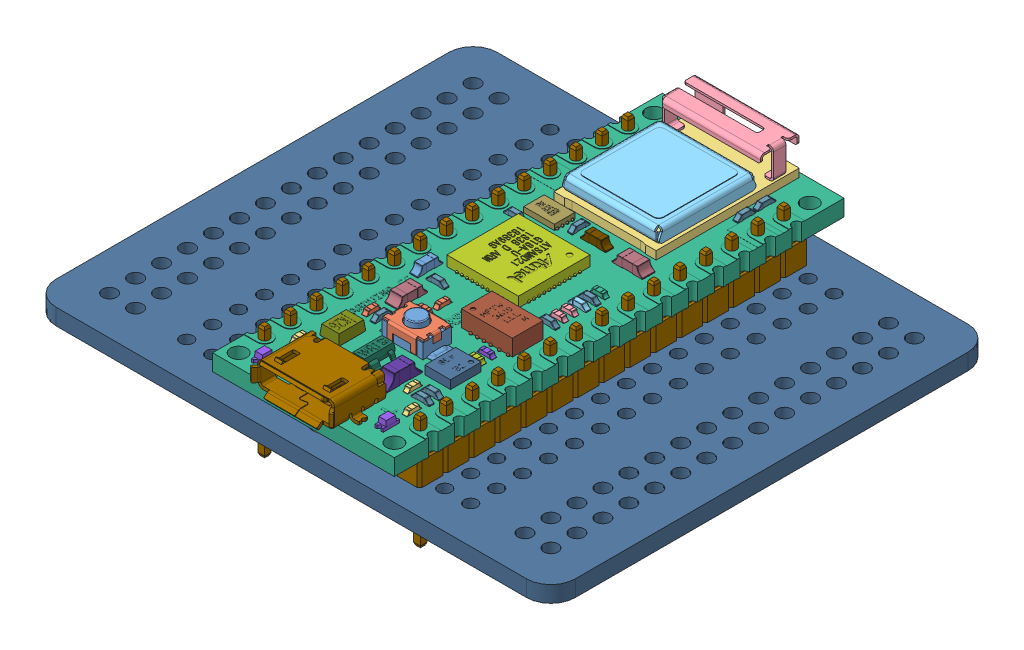
SolidWorks assembly proto assembly, configuration Default. Lengths in mm.
Overall size (50.8 13.8 45.32).
78 component instances, 28 part files, 3 mates.
Components (placement in the parent):
- arduino header subassembly-1: arduino header subassembly [Default] at (-47.2969 18.8882 11.193) size (17.78 13.8 45.32)
  - Arduino Nano 33 IoT.stp-1: Arduino Nano 33 IoT.stp [Default] at origin size (17.78 5.55 45.32)
    - Reser Button.stp-1: Reser Button.stp [Default] at (0 0.8 10.91) size (5.21 2.15 3)
      - User Library-arduino_nano_reset core.stp-1: User Library-arduino_nano_reset core.stp [Default] at origin size (5.21 2.15 2.8)
      - User Library-arduino_nano_reset shell.stp-1: User Library-arduino_nano_reset shell.stp [Default] at (0 1.65 0) x (0 0 1) z (-1 0 0) size (3 1.65 4)
    - NINA-W102 Module.stp-1: NINA-W102 Module.stp [Default] at (0 0.85 -14.5) x (0 0 -1) z (1 0 0) size (14 3.85 10)
      - NINA-W102 Body.stp-1: NINA-W102 Body.stp [Default] at origin size (14 0.85 10)
      - NINA-W102 Antenna.stp-1: NINA-W102 Antenna.stp [Default] at (7 0.8 0) size (3.8 3 10)
      - NINA-W102 Cover.stp-1: NINA-W102 Cover.stp [Default] at (-1.7 2 0) x (0 0 1) z (-1 0 0) size (9.5 1.45 9.6)
    - Nano_33IoT Body.stp-1: Nano_33IoT Body.stp [Default] at origin size (17.78 1.75 44)
    - atmegaSAMD21.stp-1: atmegaSAMD21.stp [Default] at (-1.21 0.82 -0.24) x (0 0 -1) z (1 0 0) size (7.23 1.02 7.23)
    - HSMG-C190 LED.stp-1: HSMG-C190 LED.stp [Default] at (5.79 0.8 19.6) x (0 0 1) z (-1 0 0) size (1.6 0.8 0.8)
    - HSMG-C190 LED.stp-2: HSMG-C190 LED.stp [Default] at (-5.81 0.8 20.1) x (0 0 1) z (-1 0 0) size (1.6 0.8 0.8)
    - ZX62-AB-5PA Micro USB.stp-1: ZX62-AB-5PA Micro USB.stp [Default] at (0 2.22 19.2) size (8.81 3.08 5.64)
    - LSM6DS3 Accelerometer.stp-1: LSM6DS3 Accelerometer.stp [Default] at (4.6275 0.82 12) x (-1 0 0) z (0 0 -1) size (2.5 0.85 3)
    - MPM3610 Step-Down Module.stp-1: MPM3610 Step-Down Module.stp [Default] at (3.69 1.65 6.25) x (0 0 1) z (-1 0 0) size (3.3 1.65 5.15)
    - ATECC608A No Lead Crypto Auth.stp-1: ATECC608A No Lead Crypto Auth.stp [Default] at (-4.035 0.8 -6.08) x (0 0 -1) z (1 0 0) size (2 0.55 3.3)
    - CL21A226MQCLQNC Capacitor.stp-1: CL21A226MQCLQNC Capacitor.stp [Default] at (4.44 1.225 -5.85) x (-1 0 0) z (0 0 -1) size (3 0.85 1.25)
    - TDK C1005 Capacitor.stp-1: TDK C1005 Capacitor.stp [Default] at (5.5825 1.05 -15.55) x (0 0 -1) z (1 0 0) size (1.8 0.5 0.5)
    - TDK C1005 Capacitor.stp-2: TDK C1005 Capacitor.stp [Default] at (5.5825 1.05 -17.5125) x (0 0 -1) z (1 0 0) size (1.8 0.5 0.5)
    - CL21A226MQCLQNC Capacitor.stp-2: CL21A226MQCLQNC Capacitor.stp [Default] at (-4.11 1.225 7.8375) x (0 0 1) z (-1 0 0) size (3 0.85 1.25)
    - TDK C1005 Capacitor.stp-3: TDK C1005 Capacitor.stp [Default] at (5.385 1.05 15.7375) size (1.8 0.5 0.5)
    - TDK C1005 Capacitor.stp-4: TDK C1005 Capacitor.stp [Default] at (5.385 1.05 14.7625) size (1.8 0.5 0.5)
    - PRTR5V0U2X Protection Diode.stp-1: PRTR5V0U2X Protection Diode.stp [Default] at (-0.41 1.45 14.77) x (0 0 -1) z (1 0 0) size (3 1.1 2.5)
    - PMEG6020AELR Diode.stp-1: PMEG6020AELR Diode.stp [Default] at (-4.06 0.85 14.1) x (0 0 1) z (-1 0 0) size (3.3 1.11 1.9)
    - C0805C472KDRACTU Capacitor.stp-1: C0805C472KDRACTU Capacitor.stp [Default] at (2.415 1.425 15.1325) x (0 0 1) z (-1 0 0) size (3.5 1.25 1.25)
    - TDK C1005 Capacitor.stp-5: TDK C1005 Capacitor.stp [Default] at (-1.52 1.05 -6.46) x (0 0 -1) z (1 0 0) size (1.8 0.5 0.5)
    - BLM18PG471SN1D Ferrite Bead.stp-1: BLM18PG471SN1D Ferrite Bead.stp [Default] at (0.61 1.2 -6.1) x (-1 0 0) z (0 0 -1) size (2.5 0.8 0.8)
    - TDK C1005 Capacitor.stp-6: TDK C1005 Capacitor.stp [Default] at (-5.66 1.05 -4.35) x (-1 0 0) z (0 0 -1) size (1.8 0.5 0.5)
    - TDK C1005 Capacitor.stp-7: TDK C1005 Capacitor.stp [Default] at (-3.64 1.05 10.73) x (0 0 1) z (-1 0 0) size (1.8 0.5 0.5)
    - TDK C1005 Capacitor.stp-8: TDK C1005 Capacitor.stp [Default] at (-3.79 1.05 5.1) size (1.8 0.5 0.5)
    - GRM188R61E475KE11D Capacitor.stp-1: GRM188R61E475KE11D Capacitor.stp [Default] at (-5.59 1.2 4.4) x (0 0 1) z (-1 0 0) size (2.5 0.8 0.8)
    - RC0402FR-07100KL Resistor.stp-1: RC0402FR-07100KL Resistor.stp [Default] at (-2.01 1 8.1625) x (-1 0 0) z (0 0 -1) size (1.48 0.48 0.64)
    - RC0402FR-07100KL Resistor.stp-2: RC0402FR-07100KL Resistor.stp [Default] at (-1.6975 1 6.7125) x (0 0 1) z (-1 0 0) size (1.48 0.48 0.64)
    - RC0402FR-07330RL Resistor.stp-1: RC0402FR-07330RL Resistor.stp [Default] at (-5.81 1 16.6) x (0 0 1) z (-1 0 0) size (1.48 0.48 0.64)
    - RC0402FR-07330RL Resistor.stp-2: RC0402FR-07330RL Resistor.stp [Default] at (5.8025 1 17.2) x (0 0 1) z (-1 0 0) size (1.48 0.48 0.64)
    - RC0402FR-07330RL Resistor.stp-3: RC0402FR-07330RL Resistor.stp [Default] at (3.915 1 15.2325) x (0 0 1) z (-1 0 0) size (1.48 0.48 0.64)
    - TDK C1005 Capacitor.stp-9: TDK C1005 Capacitor.stp [Default] at (5.09 1.05 3.1) x (-1 0 0) z (0 0 -1) size (1.8 0.5 0.5)
    - RC0402FR-074K7L Resistor.stp-1: RC0402FR-074K7L Resistor.stp [Default] at (5.09 1 2.1) size (1.48 0.48 0.64)
    - RC0402FR-074K7L Resistor.stp-2: RC0402FR-074K7L Resistor.stp [Default] at (5.09 1 1.1) x (-1 0 0) z (0 0 -1) size (1.48 0.48 0.64)
    - GRM155R61E105KA12D Capacitor.stp-1: GRM155R61E105KA12D Capacitor.stp [Default] at (5.09 1.05 0.1) size (1.8 0.5 0.5)
    - TDK C1005 Capacitor.stp-10: TDK C1005 Capacitor.stp [Default] at (5.09 1.05 -0.9) x (-1 0 0) z (0 0 -1) size (1.8 0.5 0.5)
    - RC0402FR-071KL Resistor.stp-1: RC0402FR-071KL Resistor.stp [Default] at (5.09 1 -1.9) x (-1 0 0) z (0 0 -1) size (1.48 0.48 0.64)
    - RC0402FR-07100KL Resistor.stp-3: RC0402FR-07100KL Resistor.stp [Default] at (-5.74 1 -13.5) x (0 0 -1) z (1 0 0) size (1.48 0.48 0.64)
    - RC0402FR-07100KL Resistor.stp-4: RC0402FR-07100KL Resistor.stp [Default] at (-4.64 1 10.73) x (0 0 1) z (-1 0 0) size (1.48 0.48 0.64)
    - AC0402JR-0724KL Resistor.stp-1: AC0402JR-0724KL Resistor.stp [Default] at (4.665 0.985 9.725) size (1.48 0.39 0.56)
    - AC0402JR-0775KL Resistor.stp-1: AC0402JR-0775KL Resistor.stp [Default] at (4.665 0.985 8.725) size (1.48 0.39 0.56)
  - 1x_Male_Pin_2.54_mm-1: 1x_Male_Pin_2.54_mm [Default] at (-7.945 2.15 -17.695) x (0 0 1) z (1 0 0) size (2.54 11.1 2.4)
  - 1x_Male_Pin_2.54_mm-2: 1x_Male_Pin_2.54_mm [Default] at (7.295 2.15 -17.695) x (0 0 1) z (1 0 0) size (2.54 11.1 2.4)
  - 1x_Male_Pin_2.54_mm-3: 1x_Male_Pin_2.54_mm [Default] at (-7.945 2.15 -15.155) x (0 0 1) z (1 0 0) size (2.54 11.1 2.4)
  - 1x_Male_Pin_2.54_mm-4: 1x_Male_Pin_2.54_mm [Default] at (7.295 2.15 -15.155) x (0 0 1) z (1 0 0) size (2.54 11.1 2.4)
  - 1x_Male_Pin_2.54_mm-5: 1x_Male_Pin_2.54_mm [Default] at (-7.945 2.15 -12.615) x (0 0 1) z (1 0 0) size (2.54 11.1 2.4)
  - 1x_Male_Pin_2.54_mm-6: 1x_Male_Pin_2.54_mm [Default] at (7.295 2.15 -12.615) x (0 0 1) z (1 0 0) size (2.54 11.1 2.4)
  - 1x_Male_Pin_2.54_mm-7: 1x_Male_Pin_2.54_mm [Default] at (-7.945 2.15 -10.075) x (0 0 1) z (1 0 0) size (2.54 11.1 2.4)
  - 1x_Male_Pin_2.54_mm-8: 1x_Male_Pin_2.54_mm [Default] at (7.295 2.15 -10.075) x (0 0 1) z (1 0 0) size (2.54 11.1 2.4)
  - 1x_Male_Pin_2.54_mm-9: 1x_Male_Pin_2.54_mm [Default] at (-7.945 2.15 -7.535) x (0 0 1) z (1 0 0) size (2.54 11.1 2.4)
  - 1x_Male_Pin_2.54_mm-10: 1x_Male_Pin_2.54_mm [Default] at (7.295 2.15 -7.535) x (0 0 1) z (1 0 0) size (2.54 11.1 2.4)
  - 1x_Male_Pin_2.54_mm-11: 1x_Male_Pin_2.54_mm [Default] at (-7.945 2.15 -4.995) x (0 0 1) z (1 0 0) size (2.54 11.1 2.4)
  - 1x_Male_Pin_2.54_mm-12: 1x_Male_Pin_2.54_mm [Default] at (7.295 2.15 -4.995) x (0 0 1) z (1 0 0) size (2.54 11.1 2.4)
  - 1x_Male_Pin_2.54_mm-13: 1x_Male_Pin_2.54_mm [Default] at (-7.945 2.15 -2.455) x (0 0 1) z (1 0 0) size (2.54 11.1 2.4)
  - 1x_Male_Pin_2.54_mm-14: 1x_Male_Pin_2.54_mm [Default] at (7.295 2.15 -2.455) x (0 0 1) z (1 0 0) size (2.54 11.1 2.4)
  - 1x_Male_Pin_2.54_mm-15: 1x_Male_Pin_2.54_mm [Default] at (-7.945 2.15 0.085) x (0 0 1) z (1 0 0) size (2.54 11.1 2.4)
  - 1x_Male_Pin_2.54_mm-16: 1x_Male_Pin_2.54_mm [Default] at (7.295 2.15 0.085) x (0 0 1) z (1 0 0) size (2.54 11.1 2.4)
  - 1x_Male_Pin_2.54_mm-17: 1x_Male_Pin_2.54_mm [Default] at (-7.945 2.15 2.625) x (0 0 1) z (1 0 0) size (2.54 11.1 2.4)
  - 1x_Male_Pin_2.54_mm-18: 1x_Male_Pin_2.54_mm [Default] at (7.295 2.15 2.625) x (0 0 1) z (1 0 0) size (2.54 11.1 2.4)
  - 1x_Male_Pin_2.54_mm-19: 1x_Male_Pin_2.54_mm [Default] at (-7.945 2.15 5.165) x (0 0 1) z (1 0 0) size (2.54 11.1 2.4)
  - 1x_Male_Pin_2.54_mm-20: 1x_Male_Pin_2.54_mm [Default] at (7.295 2.15 5.165) x (0 0 1) z (1 0 0) size (2.54 11.1 2.4)
  - 1x_Male_Pin_2.54_mm-21: 1x_Male_Pin_2.54_mm [Default] at (-7.945 2.15 7.705) x (0 0 1) z (1 0 0) size (2.54 11.1 2.4)
  - 1x_Male_Pin_2.54_mm-22: 1x_Male_Pin_2.54_mm [Default] at (7.295 2.15 7.705) x (0 0 1) z (1 0 0) size (2.54 11.1 2.4)
  - 1x_Male_Pin_2.54_mm-23: 1x_Male_Pin_2.54_mm [Default] at (-7.945 2.15 10.245) x (0 0 1) z (1 0 0) size (2.54 11.1 2.4)
  - 1x_Male_Pin_2.54_mm-24: 1x_Male_Pin_2.54_mm [Default] at (7.295 2.15 10.245) x (0 0 1) z (1 0 0) size (2.54 11.1 2.4)
  - 1x_Male_Pin_2.54_mm-25: 1x_Male_Pin_2.54_mm [Default] at (-7.945 2.15 12.785) x (0 0 1) z (1 0 0) size (2.54 11.1 2.4)
  - 1x_Male_Pin_2.54_mm-26: 1x_Male_Pin_2.54_mm [Default] at (7.295 2.15 12.785) x (0 0 1) z (1 0 0) size (2.54 11.1 2.4)
  - 1x_Male_Pin_2.54_mm-27: 1x_Male_Pin_2.54_mm [Default] at (-7.945 2.15 15.325) x (0 0 1) z (1 0 0) size (2.54 11.1 2.4)
  - 1x_Male_Pin_2.54_mm-28: 1x_Male_Pin_2.54_mm [Default] at (7.295 2.15 15.325) x (0 0 1) z (1 0 0) size (2.54 11.1 2.4)
  - 1x_Male_Pin_2.54_mm-29: 1x_Male_Pin_2.54_mm [Default] at (-7.945 2.15 17.865) x (0 0 1) z (1 0 0) size (2.54 11.1 2.4)
  - 1x_Male_Pin_2.54_mm-30: 1x_Male_Pin_2.54_mm [Default] at (7.295 2.15 17.865) x (0 0 1) z (1 0 0) size (2.54 11.1 2.4)
- QtrProtoBoard-1: QtrProtoBoard [Default] at (-48.6435 14.1507 11.4479) x (0 0 -1) z (1 0 0) size (43.18 1.59 50.8)
Mates (geometry in assembly coordinates):
- Concentric1: concentric anti-aligned: circle of arduino header subassembly-1/Arduino Nano 33 IoT.stp-1/Nano_33IoT Body.stp-1; circle of QtrProtoBoard-1
- Parallel1: parallel aligned: plane of arduino header subassembly-1/Arduino Nano 33 IoT.stp-1/Nano_33IoT Body.stp-1 through (-38.4069 18.8882 -10.807) normal (0 0 -1); plane of QtrProtoBoard-1 through (-23.2435 18.0882 -10.1421) normal (0 0 -1)
- Coincident3: coincident anti-aligned: plane of arduino header subassembly-1/1x_Male_Pin_2.54_mm-30 through (-40.0019 15.7382 29.058) normal (0 -1 0); plane of QtrProtoBoard-1 through (-48.6435 18.0882 11.4479) normal (0 1 0)
